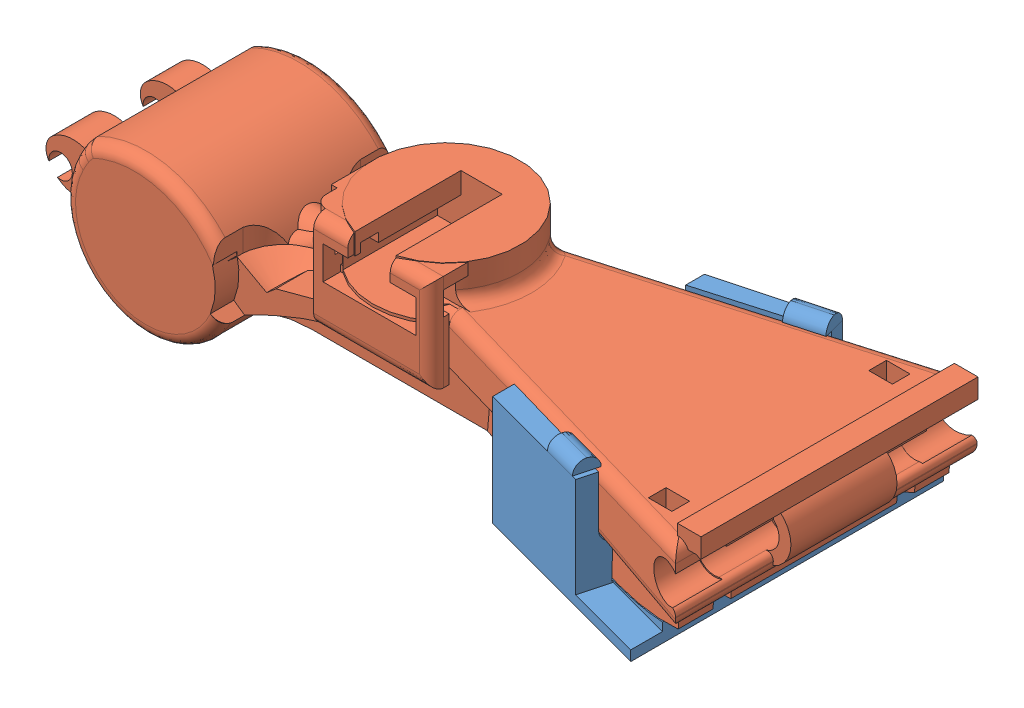
SolidWorks assembly Shell foot, configuration Default. Lengths in mm.
Overall size (158.01 42.47 67.41).
2 component instances, 2 part files, 0 mates.
Components (placement in the parent):
- foot shell-1: foot shell [Default] at (14.4585 74.4576 115.7855) size (40.64 26.26 67.41)
- New foot-1: New foot [Default] at (-73.3855 116.8013 116.0075) size (158.01 38.61 65.23)
